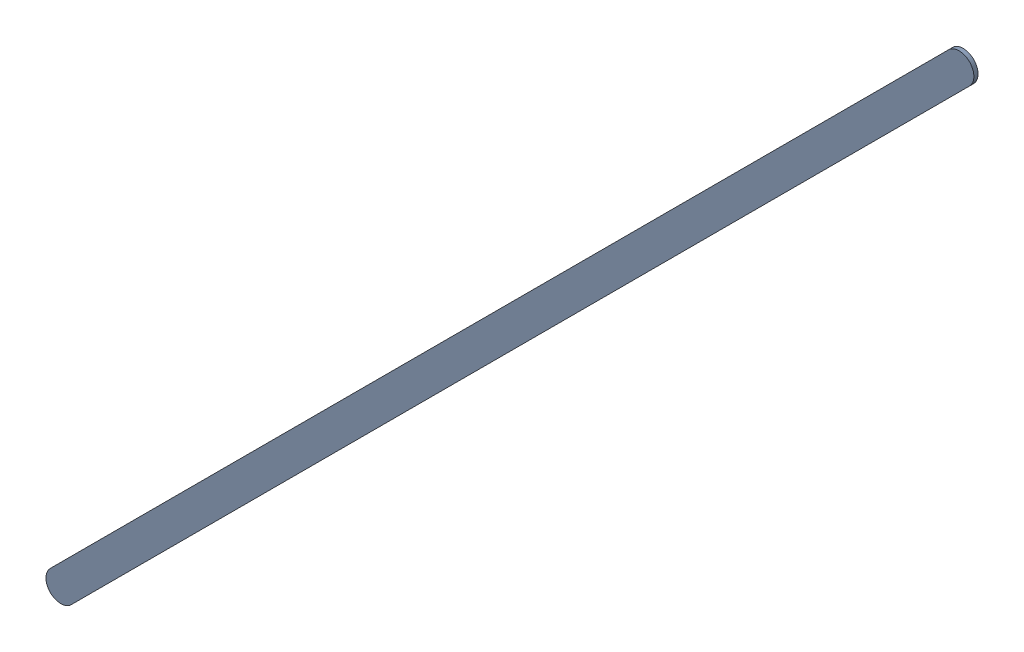
SolidWorks assembly Track (10.2mm,53.1mm)(17.9mm,60.8mm) on Top Layer, configuration Predeterminado. Lengths in mm.
Overall size (7.95 7.95 0.04).
2 component instances, 1 part files, 0 mates.
Components (placement in the parent):
- Track (10.2mm,53.1mm)(17.9mm,60.8mm) on Top Layer-1-1: Track (10.2mm,53.1mm)(17.9mm,60.8mm) on Top Layer-1 [Predeterminado] at (-68.317 -44.187 -0.0457) size (7.95 7.95 0.04)
  - Track (10.2mm,53.1mm)(17.9mm,60.8mm) on Top Layer-Part-1-1: Track (10.2mm,53.1mm)(17.9mm,60.8mm) on Top Layer-Part-1 [Predeterminado] at origin size (7.95 7.95 0.04)
